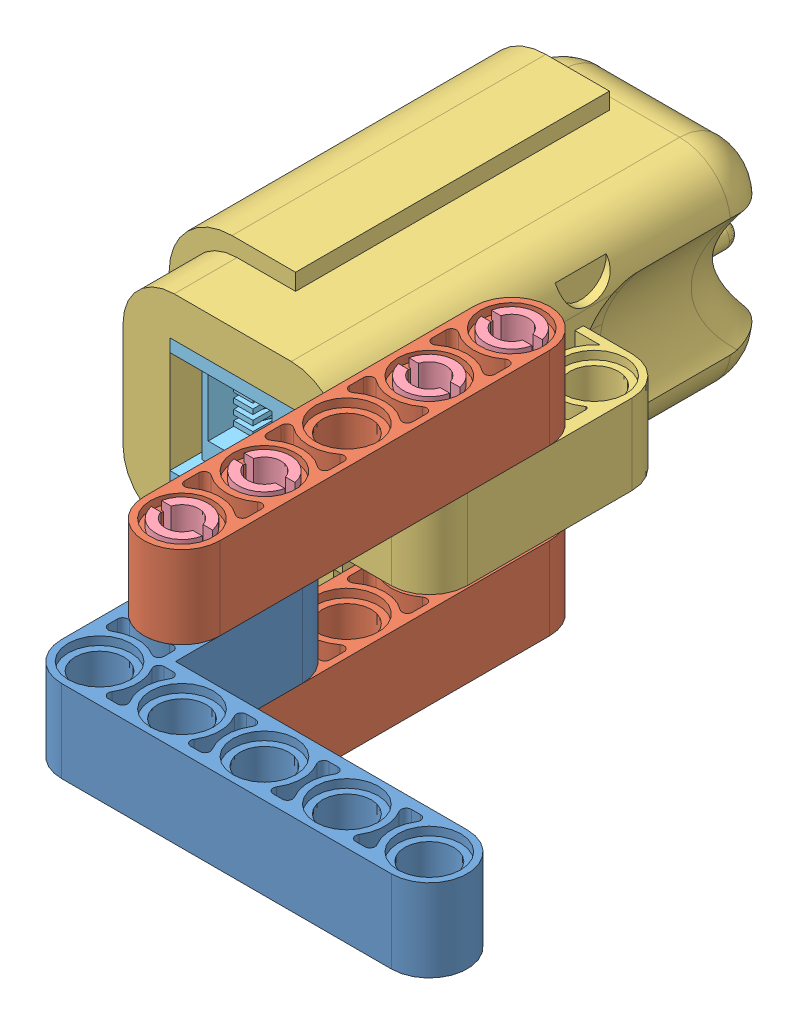
SolidWorks assembly Light Sensor, configuration Default. Lengths in mm.
Overall size (63.86 24.28 77.33).
9 component instances, 5 part files, 23 mates.
Components (placement in the parent):
- beam_angle_5x3-1: beam_angle_5x3 [Default] at (32.26 0 0) size (39.7 8.07 23.57)
- beam_5-1: beam_5 [Default] at (0 -4.0325 -40.325) x (0 0 1) z (1 0 0) size (39.7 8.06 7.44)
- beam_5-2: beam_5 [Default] at (0 12.0975 -40.325) x (0 0 1) z (1 0 0) size (39.7 8.06 7.44)
- sensor_light-1: sensor_light [Default] at (-15.51 0.1075 -50.04) x (0 1 0) z (1 0 0) size (24.05 45.24 31.6)
- conn_3-1: conn_3 [Default] at (0 0.0325 -8.065) size (6.15 24.2 6.07)
- conn_3-2: conn_3 [Default] at (0 0.0325 -16.13) size (6.15 24.2 6.07)
- conn_3-3: conn_3 [Default] at (0 0.0325 -40.325) x (-1 0 0) z (0 0 -1) size (6.15 24.2 6.07)
- conn_3-4: conn_3 [Default] at (0 0.0325 -32.26) size (6.15 24.2 6.07)
- socket-1: socket [Default] at (-14.16 0.1075 -28.54) x (0 -1 0) z (0 0 -1) size (12.5 15 12.59)
Mates (geometry in assembly coordinates):
- Concentric113: concentric: cylinder of beam_angle_5x3-1 through (0 -3.2175 0) axis (0 1 0) radius 2.39; point of assembly
- Coincident102: coincident aligned: plane of ? through (32.0411 0 -2.3799) normal (0 1 0)
- Parallel5: parallel aligned: plane of ? through (32.0411 0 -2.3799) normal (1 0 0)
- Concentric102: concentric anti-aligned: cylinder of beam_angle_5x3-1 through (-0.2189 -3.2175 -10.4449) axis (0 1 0) radius 2.39; cylinder of beam_5-2 through (-0.2189 11.2825 -10.4449) axis (0 -1 0) radius 2.39
- Concentric103: concentric anti-aligned: cylinder of beam_angle_5x3-1 through (-0.2189 -3.2175 -18.5099) axis (0 1 0) radius 2.39; cylinder of beam_5-2 through (-0.2189 11.2825 -18.5099) axis (0 -1 0) radius 2.39
- Coincident90: coincident anti-aligned: plane of beam_angle_5x3-1 through (-4.7331 4.0325 1.8116) normal (0 1 0); plane of beam_5-2 through (3.6499 4.0325 -47.2251) normal (0 -1 0)
- Concentric104: concentric anti-aligned: cylinder of beam_angle_5x3-1 through (-0.2189 -3.2175 -18.5099) axis (0 1 0) radius 2.39; cylinder of beam_5-1 through (-0.2189 -4.8475 -18.5099) axis (0 -1 0) radius 2.39
- Concentric105: concentric anti-aligned: cylinder of beam_angle_5x3-1 through (-0.2189 -3.2175 -10.4449) axis (0 1 0) radius 2.39; cylinder of beam_5-1 through (-0.2189 -4.8475 -10.4449) axis (0 -1 0) radius 2.39
- Coincident91: coincident anti-aligned: plane of beam_angle_5x3-1 through (-4.7331 -4.0325 1.8116) normal (0 -1 0); plane of beam_5-1 through (3.6499 -4.0325 -47.2251) normal (0 1 0)
- Concentric106: concentric anti-aligned: cylinder of sensor_light-1 through (-0.2189 -3.0025 -42.7049) axis (0 1 0) radius 2.39; cylinder of beam_5-2 through (-0.2189 11.2825 -42.7049) axis (0 -1 0) radius 2.39
- Coincident92: coincident anti-aligned: circle of beam_5-2; cylinder of sensor_light-1 through (-0.2189 -3.0025 -34.6399) axis (0 1 0) radius 2.39
- Coincident93: coincident anti-aligned: plane of beam_5-2 through (3.6499 4.0325 -47.2251) normal (0 -1 0); plane of sensor_light-1 through (-5.1689 4.0325 -54.9613) normal (0 1 0)
- Coincident94: coincident anti-aligned: plane of sensor_light-1 through (-6.5789 -6.3925 -43.4199) normal (0 0 1); plane of socket-1 through (-21.8789 6.3575 -43.4199) normal (0 0 -1)
- Coincident95: coincident anti-aligned: plane of sensor_light-1 through (-6.8789 -5.8725 -43.6699) normal (-1 0 0); plane of socket-1 through (-6.8789 6.3575 -43.4199) normal (1 0 0)
- Coincident96: coincident anti-aligned: plane of sensor_light-1 through (-7.0889 6.3575 -43.6699) normal (0 -1 0); plane of socket-1 through (-21.8789 6.3575 -43.4199) normal (0 1 0)
- Parallel1: parallel aligned: plane of ? through (-0.2189 0.0325 -34.6399) normal (0 0 1)
- Parallel2: parallel anti-aligned: plane of ? through (-0.2189 0.0325 -42.7049) normal (0 0 -1)
- Parallel3: parallel aligned: plane of ? through (-0.2189 0.0325 -18.5099) normal (0 0 1)
- Parallel4: parallel aligned: plane of ? through (-0.2189 0.0325 -10.4449) normal (0 0 1)
- Coincident103: coincident aligned: circle of beam_5-2; circle of conn_3-1
- Coincident104: coincident aligned: circle of beam_5-2; circle of conn_3-2
- Coincident105: coincident aligned: circle of beam_5-2; circle of conn_3-4
- Coincident106: coincident aligned: circle of beam_5-2; circle of conn_3-3
